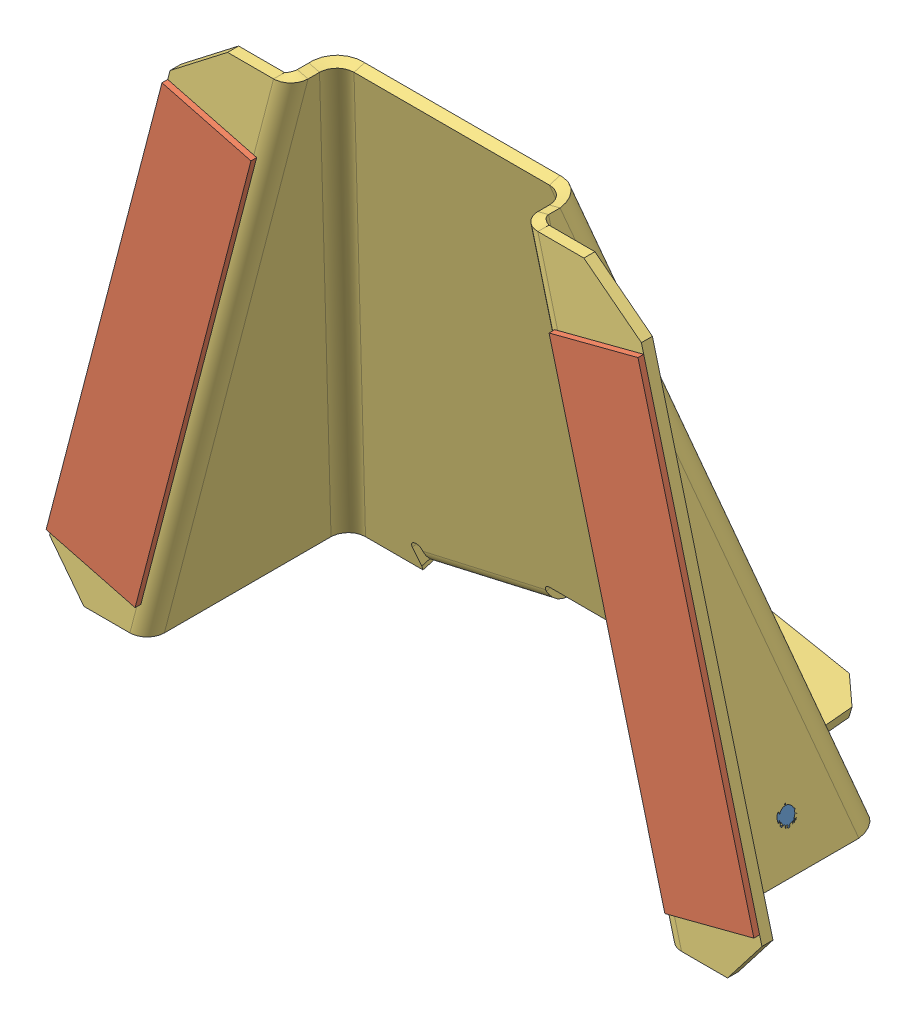
SolidWorks assembly GE-19225, configuration Default. Lengths in mm.
Overall size (196.8 153.5 83.53).
4 component instances, 3 part files, 11 mates.
Components (placement in the parent):
- PEM-FH-832-6ZI-1: PEM-FH-832-6ZI [Default] at (71.1866 13.0582 -34.1814) x (-0.967724 -0.252012 0) z (-0.111181 0.426936 -0.897421) size (9.53 6.02 6.02)
- Hook_1_5-1: Hook_1_5 [Default] at (-97.7586 14.7509 1.5875) x (0.252012 0.967724 0) z (-0.967724 0.252012 0) size (127 1.59 25.4)
- Hook_1_5-2: Hook_1_5 [Default] at (65.7532 137.6519 1.5875) x (0.252012 -0.967724 0) z (0.967724 0.252012 0) size (127 1.59 25.4)
- GE-19225-1-1: GE-19225-1 [Default] at origin size (196.8 153.5 81.94)
Mates (geometry in assembly coordinates):
- Coincident7: coincident: plane of assembly through (0 0 0) normal (0 1 0); plane of GE-19225-1-1 through (76.2 0 0) normal (0 -1 0); plane of assembly
- Coincident8: coincident: plane of assembly through (0 0 0) normal (0 0 1); plane of GE-19225-1-1 through (0 0 0) normal (0 0 1); plane of assembly
- Coincident9: coincident: plane of assembly through (0 0 0) normal (1 0 0); plane of GE-19225-1-1 through (0 0 0) normal (1 0 0); plane of assembly
- Coincident10: coincident: plane of assembly; plane of assembly; plane of Hook_1_5-1 through (-97.7586 14.7509 0) normal (-0.967724 0.252012 0); plane of GE-19225-1-1 through (-101.6 0 0) normal (-0.967724 0.252012 0)
- Distance3: distance = 2.54 mm: plane of assembly; line of assembly; plane of Hook_1_5-1 through (-65.7532 137.6519 0) normal (0.252012 0.967724 0); line of GE-19225-1-1 through (-65.113 140.1099 0) axis (0 0 -1)
- Coincident12: coincident: plane of assembly; plane of assembly; plane of Hook_1_5-2 through (65.7532 137.6519 0) normal (0.967724 0.252012 0); plane of GE-19225-1-1 through (101.6 0 0) normal (0.967724 0.252012 0)
- Distance4: distance = 2.54 mm: plane of assembly; line of assembly; plane of Hook_1_5-2 through (65.7532 137.6519 0) normal (-0.252012 0.967724 0); line of GE-19225-1-1 through (65.113 140.1099 -3.048) axis (0 0 1)
- Coincident14: coincident: plane of assembly; plane of assembly; plane of Hook_1_5-2 through (65.7532 137.6519 0) normal (0 0 -1); plane of GE-19225-1-1 through (0 0 0) normal (0 0 1)
- Coincident15: coincident: plane of assembly; plane of assembly; plane of Hook_1_5-1 through (-97.7586 14.7509 0) normal (0 0 -1); plane of GE-19225-1-1 through (0 0 0) normal (0 0 1)
- Concentric1: concentric: cylinder of PEM-FH-832-6ZI-1 through (66.5151 11.8417 -34.1814) axis (0.967724 0.252012 0) radius 2.0828; cylinder of GE-19225-1-1 through (-90.8174 -29.1303 -34.1814) axis (0.967724 0.252012 0) radius 2.0701
- Coincident16: coincident: plane of PEM-FH-832-6ZI-1 through (71.036 13.6365 -35.3969) normal (0.967724 0.252012 0); plane of GE-19225-1-1 through (69.8501 18.1901 0) normal (0.967724 0.252012 0)
